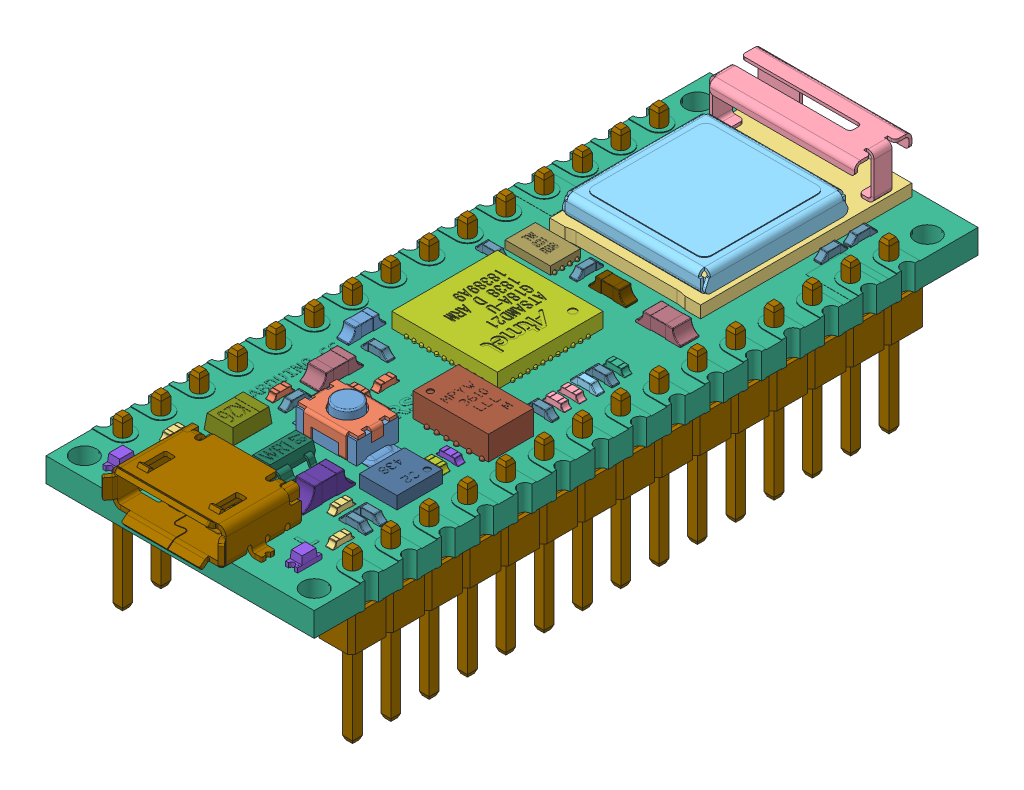
SolidWorks assembly arduino header subassembly, configuration Default. Lengths in mm.
Overall size (17.78 13.8 45.32).
76 component instances, 27 part files, 3 mates.
Components (placement in the parent):
- Arduino Nano 33 IoT.stp-1: Arduino Nano 33 IoT.stp [Default] at origin size (17.78 5.55 45.32)
  - Reser Button.stp-1: Reser Button.stp [Default] at (0 0.8 10.91) size (5.21 2.15 3)
    - User Library-arduino_nano_reset core.stp-1: User Library-arduino_nano_reset core.stp [Default] at origin size (5.21 2.15 2.8)
    - User Library-arduino_nano_reset shell.stp-1: User Library-arduino_nano_reset shell.stp [Default] at (0 1.65 0) x (0 0 1) z (-1 0 0) size (3 1.65 4)
  - NINA-W102 Module.stp-1: NINA-W102 Module.stp [Default] at (0 0.85 -14.5) x (0 0 -1) z (1 0 0) size (14 3.85 10)
    - NINA-W102 Body.stp-1: NINA-W102 Body.stp [Default] at origin size (14 0.85 10)
    - NINA-W102 Antenna.stp-1: NINA-W102 Antenna.stp [Default] at (7 0.8 0) size (3.8 3 10)
    - NINA-W102 Cover.stp-1: NINA-W102 Cover.stp [Default] at (-1.7 2 0) x (0 0 1) z (-1 0 0) size (9.5 1.45 9.6)
  - Nano_33IoT Body.stp-1: Nano_33IoT Body.stp [Default] at origin size (17.78 1.75 44)
  - atmegaSAMD21.stp-1: atmegaSAMD21.stp [Default] at (-1.21 0.82 -0.24) x (0 0 -1) z (1 0 0) size (7.23 1.02 7.23)
  - HSMG-C190 LED.stp-1: HSMG-C190 LED.stp [Default] at (5.79 0.8 19.6) x (0 0 1) z (-1 0 0) size (1.6 0.8 0.8)
  - HSMG-C190 LED.stp-2: HSMG-C190 LED.stp [Default] at (-5.81 0.8 20.1) x (0 0 1) z (-1 0 0) size (1.6 0.8 0.8)
  - ZX62-AB-5PA Micro USB.stp-1: ZX62-AB-5PA Micro USB.stp [Default] at (0 2.22 19.2) size (8.81 3.08 5.64)
  - LSM6DS3 Accelerometer.stp-1: LSM6DS3 Accelerometer.stp [Default] at (4.6275 0.82 12) x (-1 0 0) z (0 0 -1) size (2.5 0.85 3)
  - MPM3610 Step-Down Module.stp-1: MPM3610 Step-Down Module.stp [Default] at (3.69 1.65 6.25) x (0 0 1) z (-1 0 0) size (3.3 1.65 5.15)
  - ATECC608A No Lead Crypto Auth.stp-1: ATECC608A No Lead Crypto Auth.stp [Default] at (-4.035 0.8 -6.08) x (0 0 -1) z (1 0 0) size (2 0.55 3.3)
  - CL21A226MQCLQNC Capacitor.stp-1: CL21A226MQCLQNC Capacitor.stp [Default] at (4.44 1.225 -5.85) x (-1 0 0) z (0 0 -1) size (3 0.85 1.25)
  - TDK C1005 Capacitor.stp-1: TDK C1005 Capacitor.stp [Default] at (5.5825 1.05 -15.55) x (0 0 -1) z (1 0 0) size (1.8 0.5 0.5)
  - TDK C1005 Capacitor.stp-2: TDK C1005 Capacitor.stp [Default] at (5.5825 1.05 -17.5125) x (0 0 -1) z (1 0 0) size (1.8 0.5 0.5)
  - CL21A226MQCLQNC Capacitor.stp-2: CL21A226MQCLQNC Capacitor.stp [Default] at (-4.11 1.225 7.8375) x (0 0 1) z (-1 0 0) size (3 0.85 1.25)
  - TDK C1005 Capacitor.stp-3: TDK C1005 Capacitor.stp [Default] at (5.385 1.05 15.7375) size (1.8 0.5 0.5)
  - TDK C1005 Capacitor.stp-4: TDK C1005 Capacitor.stp [Default] at (5.385 1.05 14.7625) size (1.8 0.5 0.5)
  - PRTR5V0U2X Protection Diode.stp-1: PRTR5V0U2X Protection Diode.stp [Default] at (-0.41 1.45 14.77) x (0 0 -1) z (1 0 0) size (3 1.1 2.5)
  - PMEG6020AELR Diode.stp-1: PMEG6020AELR Diode.stp [Default] at (-4.06 0.85 14.1) x (0 0 1) z (-1 0 0) size (3.3 1.11 1.9)
  - C0805C472KDRACTU Capacitor.stp-1: C0805C472KDRACTU Capacitor.stp [Default] at (2.415 1.425 15.1325) x (0 0 1) z (-1 0 0) size (3.5 1.25 1.25)
  - TDK C1005 Capacitor.stp-5: TDK C1005 Capacitor.stp [Default] at (-1.52 1.05 -6.46) x (0 0 -1) z (1 0 0) size (1.8 0.5 0.5)
  - BLM18PG471SN1D Ferrite Bead.stp-1: BLM18PG471SN1D Ferrite Bead.stp [Default] at (0.61 1.2 -6.1) x (-1 0 0) z (0 0 -1) size (2.5 0.8 0.8)
  - TDK C1005 Capacitor.stp-6: TDK C1005 Capacitor.stp [Default] at (-5.66 1.05 -4.35) x (-1 0 0) z (0 0 -1) size (1.8 0.5 0.5)
  - TDK C1005 Capacitor.stp-7: TDK C1005 Capacitor.stp [Default] at (-3.64 1.05 10.73) x (0 0 1) z (-1 0 0) size (1.8 0.5 0.5)
  - TDK C1005 Capacitor.stp-8: TDK C1005 Capacitor.stp [Default] at (-3.79 1.05 5.1) size (1.8 0.5 0.5)
  - GRM188R61E475KE11D Capacitor.stp-1: GRM188R61E475KE11D Capacitor.stp [Default] at (-5.59 1.2 4.4) x (0 0 1) z (-1 0 0) size (2.5 0.8 0.8)
  - RC0402FR-07100KL Resistor.stp-1: RC0402FR-07100KL Resistor.stp [Default] at (-2.01 1 8.1625) x (-1 0 0) z (0 0 -1) size (1.48 0.48 0.64)
  - RC0402FR-07100KL Resistor.stp-2: RC0402FR-07100KL Resistor.stp [Default] at (-1.6975 1 6.7125) x (0 0 1) z (-1 0 0) size (1.48 0.48 0.64)
  - RC0402FR-07330RL Resistor.stp-1: RC0402FR-07330RL Resistor.stp [Default] at (-5.81 1 16.6) x (0 0 1) z (-1 0 0) size (1.48 0.48 0.64)
  - RC0402FR-07330RL Resistor.stp-2: RC0402FR-07330RL Resistor.stp [Default] at (5.8025 1 17.2) x (0 0 1) z (-1 0 0) size (1.48 0.48 0.64)
  - RC0402FR-07330RL Resistor.stp-3: RC0402FR-07330RL Resistor.stp [Default] at (3.915 1 15.2325) x (0 0 1) z (-1 0 0) size (1.48 0.48 0.64)
  - TDK C1005 Capacitor.stp-9: TDK C1005 Capacitor.stp [Default] at (5.09 1.05 3.1) x (-1 0 0) z (0 0 -1) size (1.8 0.5 0.5)
  - RC0402FR-074K7L Resistor.stp-1: RC0402FR-074K7L Resistor.stp [Default] at (5.09 1 2.1) size (1.48 0.48 0.64)
  - RC0402FR-074K7L Resistor.stp-2: RC0402FR-074K7L Resistor.stp [Default] at (5.09 1 1.1) x (-1 0 0) z (0 0 -1) size (1.48 0.48 0.64)
  - GRM155R61E105KA12D Capacitor.stp-1: GRM155R61E105KA12D Capacitor.stp [Default] at (5.09 1.05 0.1) size (1.8 0.5 0.5)
  - TDK C1005 Capacitor.stp-10: TDK C1005 Capacitor.stp [Default] at (5.09 1.05 -0.9) x (-1 0 0) z (0 0 -1) size (1.8 0.5 0.5)
  - RC0402FR-071KL Resistor.stp-1: RC0402FR-071KL Resistor.stp [Default] at (5.09 1 -1.9) x (-1 0 0) z (0 0 -1) size (1.48 0.48 0.64)
  - RC0402FR-07100KL Resistor.stp-3: RC0402FR-07100KL Resistor.stp [Default] at (-5.74 1 -13.5) x (0 0 -1) z (1 0 0) size (1.48 0.48 0.64)
  - RC0402FR-07100KL Resistor.stp-4: RC0402FR-07100KL Resistor.stp [Default] at (-4.64 1 10.73) x (0 0 1) z (-1 0 0) size (1.48 0.48 0.64)
  - AC0402JR-0724KL Resistor.stp-1: AC0402JR-0724KL Resistor.stp [Default] at (4.665 0.985 9.725) size (1.48 0.39 0.56)
  - AC0402JR-0775KL Resistor.stp-1: AC0402JR-0775KL Resistor.stp [Default] at (4.665 0.985 8.725) size (1.48 0.39 0.56)
- 1x_Male_Pin_2.54_mm-1: 1x_Male_Pin_2.54_mm [Default] at (-7.945 2.15 -17.695) x (0 0 1) z (1 0 0) size (2.54 11.1 2.4)
- 1x_Male_Pin_2.54_mm-2: 1x_Male_Pin_2.54_mm [Default] at (7.295 2.15 -17.695) x (0 0 1) z (1 0 0) size (2.54 11.1 2.4)
- 1x_Male_Pin_2.54_mm-3: 1x_Male_Pin_2.54_mm [Default] at (-7.945 2.15 -15.155) x (0 0 1) z (1 0 0) size (2.54 11.1 2.4)
- 1x_Male_Pin_2.54_mm-4: 1x_Male_Pin_2.54_mm [Default] at (7.295 2.15 -15.155) x (0 0 1) z (1 0 0) size (2.54 11.1 2.4)
- 1x_Male_Pin_2.54_mm-5: 1x_Male_Pin_2.54_mm [Default] at (-7.945 2.15 -12.615) x (0 0 1) z (1 0 0) size (2.54 11.1 2.4)
- 1x_Male_Pin_2.54_mm-6: 1x_Male_Pin_2.54_mm [Default] at (7.295 2.15 -12.615) x (0 0 1) z (1 0 0) size (2.54 11.1 2.4)
- 1x_Male_Pin_2.54_mm-7: 1x_Male_Pin_2.54_mm [Default] at (-7.945 2.15 -10.075) x (0 0 1) z (1 0 0) size (2.54 11.1 2.4)
- 1x_Male_Pin_2.54_mm-8: 1x_Male_Pin_2.54_mm [Default] at (7.295 2.15 -10.075) x (0 0 1) z (1 0 0) size (2.54 11.1 2.4)
- 1x_Male_Pin_2.54_mm-9: 1x_Male_Pin_2.54_mm [Default] at (-7.945 2.15 -7.535) x (0 0 1) z (1 0 0) size (2.54 11.1 2.4)
- 1x_Male_Pin_2.54_mm-10: 1x_Male_Pin_2.54_mm [Default] at (7.295 2.15 -7.535) x (0 0 1) z (1 0 0) size (2.54 11.1 2.4)
- 1x_Male_Pin_2.54_mm-11: 1x_Male_Pin_2.54_mm [Default] at (-7.945 2.15 -4.995) x (0 0 1) z (1 0 0) size (2.54 11.1 2.4)
- 1x_Male_Pin_2.54_mm-12: 1x_Male_Pin_2.54_mm [Default] at (7.295 2.15 -4.995) x (0 0 1) z (1 0 0) size (2.54 11.1 2.4)
- 1x_Male_Pin_2.54_mm-13: 1x_Male_Pin_2.54_mm [Default] at (-7.945 2.15 -2.455) x (0 0 1) z (1 0 0) size (2.54 11.1 2.4)
- 1x_Male_Pin_2.54_mm-14: 1x_Male_Pin_2.54_mm [Default] at (7.295 2.15 -2.455) x (0 0 1) z (1 0 0) size (2.54 11.1 2.4)
- 1x_Male_Pin_2.54_mm-15: 1x_Male_Pin_2.54_mm [Default] at (-7.945 2.15 0.085) x (0 0 1) z (1 0 0) size (2.54 11.1 2.4)
- 1x_Male_Pin_2.54_mm-16: 1x_Male_Pin_2.54_mm [Default] at (7.295 2.15 0.085) x (0 0 1) z (1 0 0) size (2.54 11.1 2.4)
- 1x_Male_Pin_2.54_mm-17: 1x_Male_Pin_2.54_mm [Default] at (-7.945 2.15 2.625) x (0 0 1) z (1 0 0) size (2.54 11.1 2.4)
- 1x_Male_Pin_2.54_mm-18: 1x_Male_Pin_2.54_mm [Default] at (7.295 2.15 2.625) x (0 0 1) z (1 0 0) size (2.54 11.1 2.4)
- 1x_Male_Pin_2.54_mm-19: 1x_Male_Pin_2.54_mm [Default] at (-7.945 2.15 5.165) x (0 0 1) z (1 0 0) size (2.54 11.1 2.4)
- 1x_Male_Pin_2.54_mm-20: 1x_Male_Pin_2.54_mm [Default] at (7.295 2.15 5.165) x (0 0 1) z (1 0 0) size (2.54 11.1 2.4)
- 1x_Male_Pin_2.54_mm-21: 1x_Male_Pin_2.54_mm [Default] at (-7.945 2.15 7.705) x (0 0 1) z (1 0 0) size (2.54 11.1 2.4)
- 1x_Male_Pin_2.54_mm-22: 1x_Male_Pin_2.54_mm [Default] at (7.295 2.15 7.705) x (0 0 1) z (1 0 0) size (2.54 11.1 2.4)
- 1x_Male_Pin_2.54_mm-23: 1x_Male_Pin_2.54_mm [Default] at (-7.945 2.15 10.245) x (0 0 1) z (1 0 0) size (2.54 11.1 2.4)
- 1x_Male_Pin_2.54_mm-24: 1x_Male_Pin_2.54_mm [Default] at (7.295 2.15 10.245) x (0 0 1) z (1 0 0) size (2.54 11.1 2.4)
- 1x_Male_Pin_2.54_mm-25: 1x_Male_Pin_2.54_mm [Default] at (-7.945 2.15 12.785) x (0 0 1) z (1 0 0) size (2.54 11.1 2.4)
- 1x_Male_Pin_2.54_mm-26: 1x_Male_Pin_2.54_mm [Default] at (7.295 2.15 12.785) x (0 0 1) z (1 0 0) size (2.54 11.1 2.4)
- 1x_Male_Pin_2.54_mm-27: 1x_Male_Pin_2.54_mm [Default] at (-7.945 2.15 15.325) x (0 0 1) z (1 0 0) size (2.54 11.1 2.4)
- 1x_Male_Pin_2.54_mm-28: 1x_Male_Pin_2.54_mm [Default] at (7.295 2.15 15.325) x (0 0 1) z (1 0 0) size (2.54 11.1 2.4)
- 1x_Male_Pin_2.54_mm-29: 1x_Male_Pin_2.54_mm [Default] at (-7.945 2.15 17.865) x (0 0 1) z (1 0 0) size (2.54 11.1 2.4)
- 1x_Male_Pin_2.54_mm-30: 1x_Male_Pin_2.54_mm [Default] at (7.295 2.15 17.865) x (0 0 1) z (1 0 0) size (2.54 11.1 2.4)
Mates (geometry in assembly coordinates):
- Coincident1: coincident anti-aligned: plane of Arduino Nano 33 IoT.stp-1/Nano_33IoT Body.stp-1 through (-8.0513 -0.85 -17.37) normal (0 -1 0); plane of 1x_Male_Pin_2.54_mm-1 through (-7.945 0.85 -17.695) normal (0 1 0)
- Distance2: distance = 4.955 mm anti-aligned: plane of 1x_Male_Pin_2.54_mm-1 through (-7.945 1.95 -17.045) normal (0 0 1); plane of Arduino Nano 33 IoT.stp-1/Nano_33IoT Body.stp-1 through (8.89 0 -22) normal (0 0 -1)
- Distance5: distance = 0.07 mm aligned: plane of 1x_Male_Pin_2.54_mm-1 through (-8.82 -3.15 -16.1) normal (-1 0 0); plane of Arduino Nano 33 IoT.stp-1/Nano_33IoT Body.stp-1 through (-8.89 0 -22) normal (-1 0 0)
